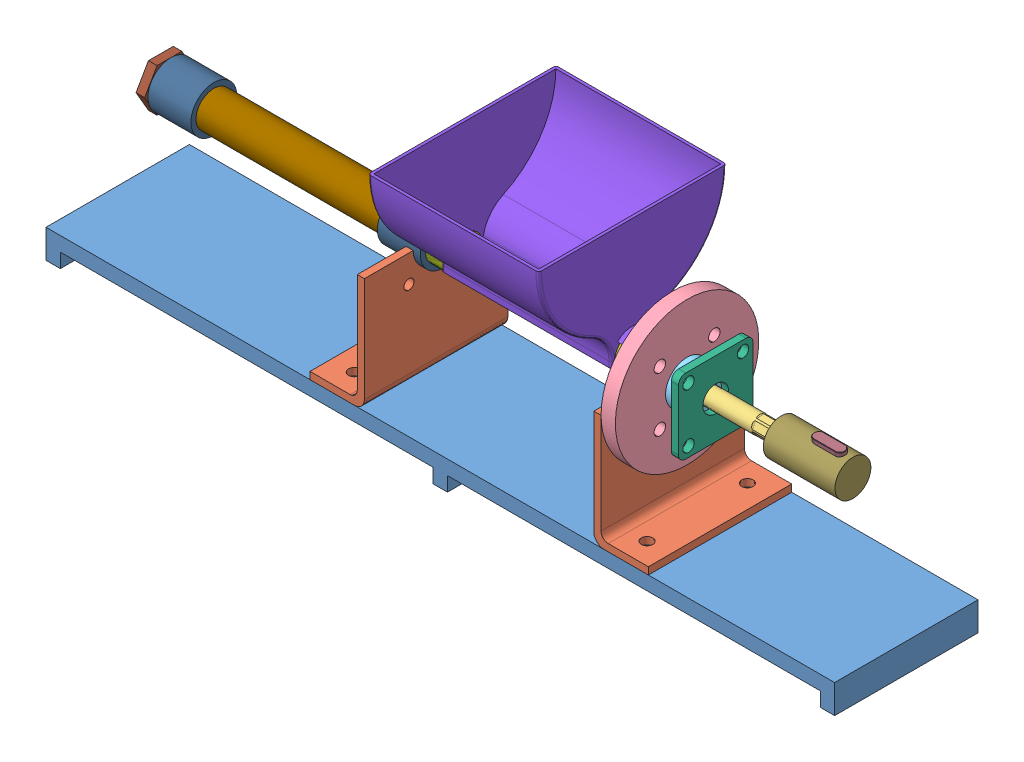
SolidWorks assembly personal, configuration Default. Lengths in mm.
Overall size (550 180 141.42).
15 component instances, 13 part files, 36 mates.
Components (placement in the parent):
- basement-1: basement [Default] at (-258.5005 -38.2238 50) size (550 20 100)
- hopper base bracket-1: hopper base bracket [Default] at (123.5995 -28.2238 50) x (0 0 -1) z (1 0 0) size (100 80 38)
- Auger drill bit-1: Auger drill bit [Default] at (219.258 51.7762 0) x (1 0 0) z (0 -0.816562 -0.577258) size (438.53 20.47 20.09)
- pipe flange-1: pipe flange [Default] at (138.5995 51.7762 0) x (0 0.707107 0.707107) z (-1 0 0) size (100 100 20)
- bronzina-1: bronzina [Default] at (153.5995 51.7762 0) x (1 0 0) z (0 0.148244 0.988951) size (15 30 30)
- auger bearing plate-1: auger bearing plate [Default] at (158.5995 25.7762 -26) x (0 0 1) z (-1 0 0) size (52 52 5)
- hopper base-1: hopper base [Default] at (-46.4005 51.7762 0) x (0 0 -1) z (1 0 0) size (25 25 180)
- tramoggia-1: tramoggia [Default] at (-18.4005 51.7762 0) x (0 0 -1) z (1 0 0) size (131 84 139)
- pipe nipple-1: pipe nipple [Default] at (-46.4005 51.7762 0) x (0 -0.304129 0.952631) z (-1 0 0) size (25 25 160)
- raccordo-1: raccordo [Default] at (-61.4005 51.7762 0) x (0 -0.933041 -0.359769) z (1 0 0) size (32 32 30)
- hopper base bracket-2: hopper base bracket [Default] at (-36.4005 -28.2238 -50) x (0 0 1) z (-1 0 0) size (100 80 38)
- nozzle2-1: nozzle2 [Default] at (-228.4005 51.7762 0) x (0 1 0) z (1 0 0) size (30 34.64 22)
- raccordo-2: raccordo [Default] at (-221.4005 51.7762 0) x (0 -0.933041 -0.359769) z (1 0 0) size (32 32 30)
- accordo motore-1: accordo motore [Default] at (254.258 51.7762 0) x (0 -0.091639 0.995792) z (-1 0 0) size (25 25 50)
- Parallel Key_KS-1: Parallel Key_KS [KS 1311 PK- 7x7-22-A] at (228.258 59.7426 0.7331) x (1 0 0) z (0 -0.091639 0.995792) size (22 7 7)
Mates (geometry in assembly coordinates):
- Coincidente1: coincident anti-aligned: plane of basement-1 through (-258.5005 -28.2238 -50) normal (0 1 0); plane of hopper base bracket-1 through (128.5995 -28.2238 50) normal (0 -1 0)
- Concentrico1: concentric aligned: cylinder of basement-1 through (145.6995 -28.2238 -35) axis (0 -1 0) radius 4; cylinder of hopper base bracket-1 through (145.6995 -23.2238 -35) axis (0 -1 0) radius 4
- Concentrico2: concentric aligned: cylinder of basement-1 through (145.6995 -28.2238 35) axis (0 -1 0) radius 4; cylinder of hopper base bracket-1 through (145.6995 -23.2238 35) axis (0 -1 0) radius 4
- Concentrico3: concentric anti-aligned: cylinder of Auger drill bit-1 through (-256.9182 51.7762 0) axis (-1 0 0) radius 6; cylinder of pipe flange-1 through (138.5995 51.7762 0) axis (1 0 0) radius 10.5
- Concentrico4: concentric anti-aligned: cylinder of hopper base bracket-1 through (128.5995 32.7762 19) axis (-1 0 0) radius 3.5; cylinder of pipe flange-1 through (128.5995 32.7762 19) axis (1 0 0) radius 4
- Concentrico5: concentric anti-aligned: cylinder of hopper base bracket-1 through (128.5995 32.7762 -19) axis (-1 0 0) radius 3.5; cylinder of pipe flange-1 through (128.5995 32.7762 -19) axis (1 0 0) radius 4
- Coincidente2: coincident anti-aligned: plane of hopper base bracket-1 through (128.5995 51.7762 0) normal (1 0 0); plane of pipe flange-1 through (128.5995 51.7762 0) normal (-1 0 0)
- Concentrico6: concentric aligned: cone of Auger drill bit-1 through (149.9732 51.7762 0) axis (1 0 0); cone of bronzina-1 through (138.5995 51.7762 0) axis (1 0 0)
- Coincidente3: coincident: cone of Auger drill bit-1 through (149.9732 51.7762 0) axis (1 0 0); circle of bronzina-1
- Concentrico8: concentric aligned: cylinder of pipe flange-1 through (128.5995 32.7762 -19) axis (1 0 0) radius 4; cylinder of auger bearing plate-1 through (153.5995 32.7762 -19) axis (1 0 0) radius 4
- Concentrico9: concentric anti-aligned: cylinder of hopper base bracket-1 through (128.5995 32.7762 19) axis (-1 0 0) radius 3.5; cylinder of auger bearing plate-1 through (153.5995 32.7762 19) axis (1 0 0) radius 4
- Coincidente4: coincident anti-aligned: plane of bronzina-1 through (153.5995 66.6105 -2.2237) normal (1 0 0); plane of auger bearing plate-1 through (153.5995 30.7762 -21) normal (-1 0 0)
- Coincidente5: coincident anti-aligned: plane of pipe flange-1 through (138.5995 51.7762 0) normal (1 0 0); plane of bronzina-1 through (138.5995 61.8039 -1.5031) normal (-1 0 0)
- Concentrico10: concentric anti-aligned: cylinder of pipe flange-1 through (118.5995 51.7762 0) axis (1 0 0) radius 15; cylinder of hopper base-1 through (133.5995 51.7762 0) axis (-1 0 0) radius 10
- Parallelo1: parallel aligned: plane of basement-1 through (-258.5005 -28.2238 -50) normal (0 1 0); plane of hopper base-1 through (98.5995 51.7762 -20) normal (0 1 0)
- Distanza1: distance = 15 mm anti-aligned: plane of pipe flange-1 through (118.5995 51.7762 0) normal (-1 0 0); plane of hopper base-1 through (133.5995 51.7762 0) normal (1 0 0)
- Concentrico12: concentric anti-aligned: cylinder of hopper base-1 through (133.5995 51.7762 0) axis (-1 0 0) radius 12.5; cylinder of tramoggia-1 through (-18.4005 51.7762 0) axis (1 0 0) radius 12.5
- Parallelo2: parallel anti-aligned: plane of hopper base-1 through (98.5995 51.7762 -20) normal (0 1 0); plane of tramoggia-1 through (100.5995 47.7762 14.5) normal (0 -1 0)
- Coincidente9: coincident aligned: plane of hopper base-1 through (98.5995 64.2762 -20) normal (-1 0 0); plane of tramoggia-1 through (98.5995 131.7762 0) normal (-1 0 0)
- Concentrico13: concentric anti-aligned: cylinder of Auger drill bit-1 through (-256.9182 51.7762 0) axis (-1 0 0) radius 9.9; cylinder of pipe nipple-1 through (-206.4005 51.7762 0) axis (1 0 0) radius 10
- Concentrico14: concentric anti-aligned: cylinder of pipe nipple-1 through (-206.4005 51.7762 0) axis (1 0 0) radius 12.5; cylinder of raccordo-1 through (-31.4005 51.7762 0) axis (-1 0 0) radius 11
- Distanza2: distance = 15 mm aligned: plane of raccordo-1 through (-31.4005 51.7762 0) normal (1 0 0); plane of pipe nipple-1 through (-46.4005 51.7762 0) normal (1 0 0)
- Distanza3: distance = 15 mm anti-aligned: plane of raccordo-1 through (-31.4005 51.7762 0) normal (1 0 0); plane of hopper base-1 through (-46.4005 51.7762 0) normal (-1 0 0)
- Coincidente13: coincident anti-aligned: plane of basement-1 through (-258.5005 -28.2238 -50) normal (0 1 0); plane of hopper base bracket-2 through (-41.4005 -28.2238 -50) normal (0 -1 0)
- Concentrico17: concentric aligned: cylinder of basement-1 through (-58.5005 -28.2238 -35) axis (0 -1 0) radius 4; cylinder of hopper base bracket-2 through (-58.5005 -23.2238 -35) axis (0 -1 0) radius 4
- Concentrico18: concentric aligned: cylinder of basement-1 through (-58.5005 -28.2238 35) axis (0 -1 0) radius 4; cylinder of hopper base bracket-2 through (-58.5005 -23.2238 35) axis (0 -1 0) radius 4
- Concentrico19: concentric anti-aligned: cylinder of pipe nipple-1 through (-206.4005 51.7762 0) axis (1 0 0) radius 12.5; cylinder of nozzle2-1 through (-206.4005 51.7762 0) axis (-1 0 0) radius 12.5
- Parallelo3: parallel anti-aligned: plane of basement-1 through (-258.5005 -28.2238 -50) normal (0 1 0); plane of nozzle2-1 through (-222.4005 36.7762 8.6603) normal (0 -1 0)
- Concentrico20: concentric anti-aligned: cylinder of pipe nipple-1 through (-206.4005 51.7762 0) axis (1 0 0) radius 12.5; cylinder of raccordo-2 through (-191.4005 51.7762 0) axis (-1 0 0) radius 11
- Distanza4: distance = 15 mm anti-aligned: plane of raccordo-2 through (-191.4005 51.7762 0) normal (1 0 0); plane of pipe nipple-1 through (-206.4005 51.7762 0) normal (-1 0 0)
- Distanza5: distance = 15 mm anti-aligned: plane of nozzle2-1 through (-206.4005 51.7762 0) normal (1 0 0); plane of raccordo-2 through (-221.4005 51.7762 0) normal (-1 0 0)
- Coincidente17: coincident anti-aligned: plane of Auger drill bit-1 through (219.258 47.2158 -10.4619) normal (0 -0.995792 -0.091639); plane of accordo motore-1 through (219.258 46.5904 -3.6661) normal (0 0.995792 0.091639)
- Coincidente18: coincident anti-aligned: plane of Auger drill bit-1 through (219.258 48.3127 4.8994) normal (1 0 0); plane of accordo motore-1 through (219.258 57.5441 -2.658) normal (-1 0 0)
- Concentrico21: concentric anti-aligned: cylinder of Auger drill bit-1 through (-256.9182 51.7762 0) axis (-1 0 0) radius 6; cylinder of accordo motore-1 through (204.258 51.7762 0) axis (1 0 0) radius 12.5
- Coincidente22: coincident anti-aligned: plane of accordo motore-1 through (246.758 59.7426 0.7331) normal (0 0.995792 0.091639); plane of Parallel Key_KS-1 through (250.258 60.0633 -2.7522) normal (0 -0.995792 -0.091639)
- Concentrico23: concentric anti-aligned: cylinder of accordo motore-1 through (231.758 59.7426 0.7331) axis (0 0.995792 0.091639) radius 3.5; cylinder of Parallel Key_KS-1 through (231.758 66.7131 1.3746) axis (0 -0.995792 -0.091639) radius 3.5
